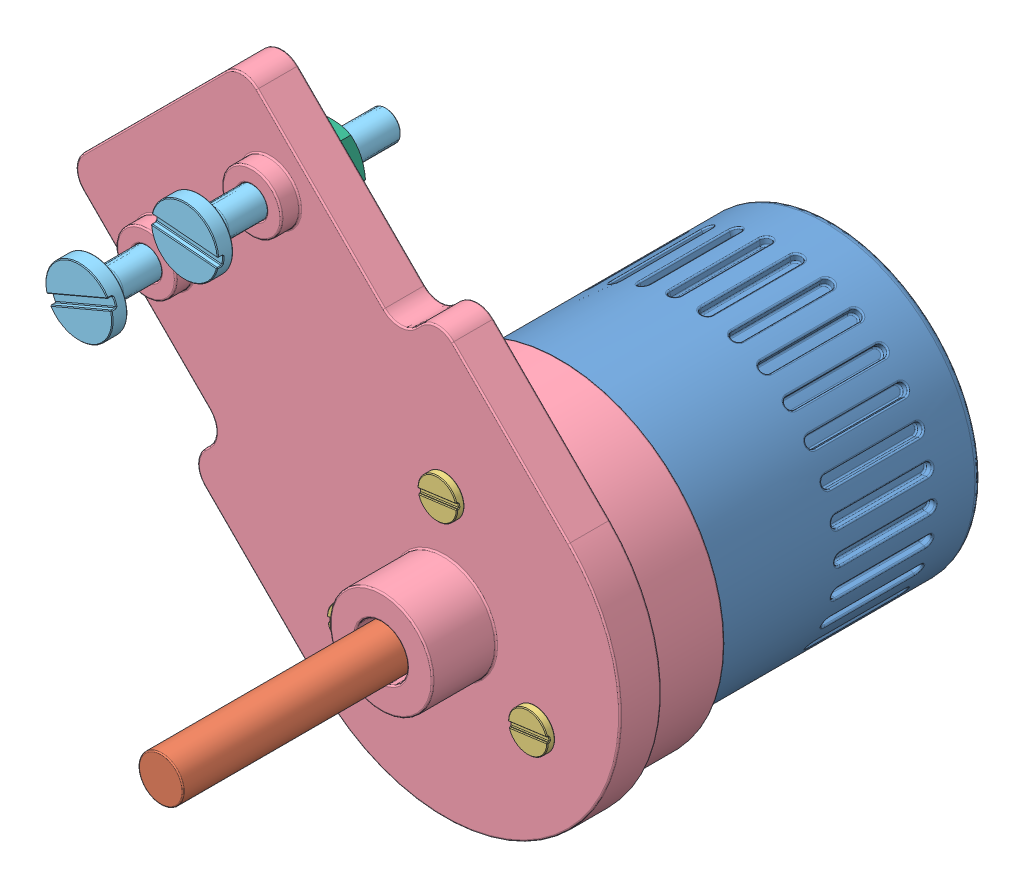
SolidWorks assembly Motor Assembly, configuration Default. Lengths in mm.
Overall size (36.41 36.41 45.5).
13 component instances, 7 part files, 7 mates.
Components (placement in the parent):
- Motor-1: Motor [Default] at (-25.3397 14.6852 35.1852) size (20 20 26)
- Motor Shaft-1: Motor Shaft [Default] at (-25.3397 14.6852 55.1852) x (0.582298 0.812976 0) z (0 0 1) size (3 3 25)
- 1.25mm screw-1: 1.25mm screw [Default] at (-25.3397 21.6852 36.1852) x (0.133353 -0.991069 0) z (0 0 -1) size (2.65 2.65 7.5)
- 1.25mm screw-2: 1.25mm screw [Default] at (-31.4018 11.1852 36.1852) x (0.133353 -0.991069 0) z (0 0 -1) size (2.65 2.65 7.5)
- 1.25mm screw-3: 1.25mm screw [Default] at (-19.2775 11.1852 36.1852) x (0.133353 -0.991069 0) z (0 0 -1) size (2.65 2.65 7.5)
- Part6^Motor Assembly-1: Part6^Motor Assembly [Default] at origin (virtual)
- Motor Mounting Bracket REALLL-1: Motor Mounting Bracket REALLL [Default] at (-125.3397 14.6852 33.4352) size (36.41 36.41 12)
- 2mm screw and nut-5: 2mm screw and nut [Default] at (-44.078 26.3524 40.9352) x (0.391837 -0.920035 0) z (0 0 -1) size (4.5 4.62 13.5)
  - 2mm screw-1: 2mm screw [Default] at origin size (4.5 4.5 13.5)
  - 2mm nut-1: 2mm nut [Default] at (0 0 7.5) size (4 4.62 1.5)
- 2mm screw and nut-6: 2mm screw and nut [Default] at (-37.0069 33.4235 40.9352) x (-0.082754 -0.99657 0) z (0 0 -1) size (4.5 4.62 13.5)
  - 2mm screw-1: 2mm screw [Default] at origin size (4.5 4.5 13.5)
  - 2mm nut-1: 2mm nut [Default] at (0 0 7.5) size (4 4.62 1.5)
Mates (geometry in assembly coordinates):
- Coincident2: coincident anti-aligned: plane of Motor-1 through (-25.3397 14.6852 30.1852) normal (0 0 1); plane of Motor Shaft-1 through (-25.3397 14.6852 30.1852) normal (0 0 -1)
- Concentric1: concentric aligned: cylinder of Motor Shaft-1 through (-25.3397 14.6852 30.1852) axis (0 0 1) radius 1.5; cylinder of Motor Mounting Bracket REALLL-1 through (-25.3397 14.6852 30.2355) axis (0 0 1) radius 1.75
- Coincident3: coincident anti-aligned: plane of 1.25mm screw-3 through (-19.2775 11.1852 36.1852) normal (0 0 -1); plane of Motor Mounting Bracket REALLL-1 through (-25.3397 14.6852 36.1852) normal (0 0 1)
- Coincident4: coincident anti-aligned: plane of Motor Mounting Bracket REALLL-1 through (-25.3397 14.6852 33.4352) normal (0 0 -1); plane of 2mm screw and nut-6/2mm nut-1 through (-37.0069 33.4235 33.4352) normal (0 0 1)
- Concentric6: concentric anti-aligned: cylinder of Motor Mounting Bracket REALLL-1 through (-37.0069 33.4235 36.1852) axis (0 0 -1) radius 1; cylinder of 2mm screw and nut-6/2mm screw-1 through (-37.0069 33.4235 28.4352) axis (0 0 1) radius 1
- Coincident5: coincident anti-aligned: plane of Motor Mounting Bracket REALLL-1 through (-25.3397 14.6852 33.4352) normal (0 0 -1); plane of 2mm screw and nut-5/2mm nut-1 through (-44.078 26.3524 33.4352) normal (0 0 1)
- Concentric8: concentric anti-aligned: cylinder of Motor Mounting Bracket REALLL-1 through (-44.078 26.3524 36.1852) axis (0 0 -1) radius 1; cylinder of 2mm screw and nut-5/2mm screw-1 through (-44.078 26.3524 28.4352) axis (0 0 1) radius 1
